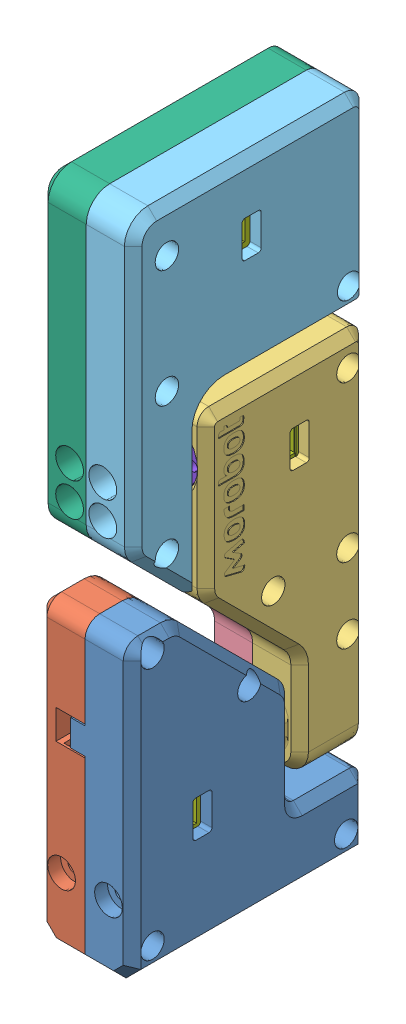
SolidWorks assembly morobot-s-RRR, configuration Standard. Lengths in mm.
Overall size (121.81 228.58 81.15).
12 component instances, 8 part files, 31 mates.
Components (placement in the parent):
- L1_1-4: L1_1 [Standard] at origin size (20.9 101 80)
- L1_2-2: L1_2 [Standard] at origin size (16.29 101 80)
- L2_1-2: L2_1 [Standard] at (-6.6119 1.3517 0) x (0.906308 -0.422618 0) z (0 0 1) size (64.27 117.88 55.7)
- L2_2-2: L2_2 [Standard] at (-6.6119 1.3517 0) x (0.906308 -0.422618 0) z (0 0 1) size (65.64 116.51 55.7)
- L3_1-2: L3_1 [Standard] at (28.5195 4.7304 0) x (0.994056 -0.10887 0) z (0 0 1) size (33.16 120.87 81.15)
- L3_2-2: L3_2 [Standard] at (28.5195 4.7304 0) x (0.994056 -0.10887 0) z (0 0 1) size (28.66 121.22 80.97)
- Motor-2: Motor [Standard] at (0.15 -0.1474 0.15) size (24.42 48.42 41)
- Motor_Drehachse-2: Motor_Drehachse [Standard] at (0.15 -0.1474 0.15) size (23.25 23.25 6.8)
- Motor-3: Motor [Standard] at (0.4 92.6052 -1.15) x (-1 0 0) z (0 0 -1) size (24.42 48.42 41)
- Motor_Drehachse-3: Motor_Drehachse [Standard] at (-5.7288 123.3848 -1.85) x (0.923728 0.383049 0) z (0 0 -1) size (23.25 23.25 6.8)
- Motor-4: Motor [Standard] at (0.25 163.324 -16.1777) size (24.42 48.42 41)
- Motor_Drehachse-4: Motor_Drehachse [Standard] at (-8.1505 165.7066 -16.1777) x (0.851084 -0.525029 0) z (0 0 1) size (23.25 23.25 6.8)
Mates (geometry in assembly coordinates):
- Deckungsgleich15: coincident anti-aligned: plane of L1_1-4 through (13 28.2474 28.15) normal (0 0 -1); plane of Motor-2 through (12.15 27.8526 28.15) normal (0 0 1)
- Deckungsgleich16: coincident anti-aligned: plane of L1_1-4 through (13 -20.1474 28.15) normal (0 0.999848 -0.017452); plane of Motor-2 through (12.15 -20.1474 28.15) normal (0 -0.999848 0.017452)
- Deckungsgleich18: coincident anti-aligned: plane of L1_1-4 through (12.15 0 0) normal (-1 0 0); plane of Motor-2 through (12.15 3.8526 8.15) normal (1 0 0)
- Konzentrisch2: concentric anti-aligned: cylinder of Motor-2 through (0.15 15.8526 -12.85) axis (0 0 1) radius 3.5; cylinder of Motor_Drehachse-2 through (0.15 15.8526 -6.05) axis (0 0 -1) radius 3.6
- Abstand2: distance = 0.7 mm anti-aligned: plane of Motor_Drehachse-2 through (0.15 15.8526 -6.05) normal (0 0 1); plane of Motor-2 through (0.15 15.8526 -5.35) normal (0 0 -1)
- Deckungsgleich20: coincident anti-aligned: plane of L1_1-4 through (0 -17.95 33) normal (-1 0 0); plane of L1_2-2 through (0 0 0) normal (1 0 0)
- Deckungsgleich21: coincident aligned: plane of L1_1-4 through (-16 -31 40) normal (0 -1 0); plane of L1_2-2 through (-16 -31 40) normal (0 -1 0)
- Deckungsgleich22: coincident aligned: plane of L1_1-4 through (0 0 40) normal (0 0 1); plane of L1_2-2 through (0 0 40) normal (0 0 1)
- Deckungsgleich23: coincident anti-aligned: plane of L2_1-2 through (13.15 72.6052 -29.15) normal (0 0 1); plane of Motor-3 through (-11.6 120.6052 -29.15) normal (0 0 -1)
- Deckungsgleich24: coincident anti-aligned: plane of L2_1-2 through (13.15 72.4298 -19.1026) normal (0 0.999848 0.017452); plane of Motor-3 through (-11.6 72.6052 -29.15) normal (0 -0.999848 -0.017452)
- Deckungsgleich25: coincident anti-aligned: plane of L2_1-2 through (12.3 50.7526 -40) normal (-1 0 0); plane of Motor-3 through (12.3 107.6052 -3.5071) normal (1 0 0)
- Konzentrisch3: concentric anti-aligned: cylinder of Motor-3 through (0.4 108.6052 11.85) axis (0 0 -1) radius 3.5; cylinder of Motor_Drehachse-3 through (0.4 108.6052 4.35) axis (0 0 1) radius 3.6
- Deckungsgleich26: coincident anti-aligned: plane of Motor-3 through (0.4 108.6052 4.35) normal (0 0 1); plane of Motor_Drehachse-3 through (0.4 108.6052 4.35) normal (0 0 -1)
- Deckungsgleich27: coincident anti-aligned: plane of L2_1-2 through (0.15 37.7526 -36.6465) normal (-1 0 0); plane of L2_2-2 through (0.15 50.7526 -40) normal (1 0 0)
- Deckungsgleich28: coincident aligned: plane of L2_1-2 through (0.15 50.7526 -40) normal (0 0 -1); plane of L2_2-2 through (0.15 50.7526 -40) normal (0 0 -1)
- Deckungsgleich29: coincident aligned: plane of L2_1-2 through (16.15 125.7526 -17) normal (0 1 0); plane of L2_2-2 through (16.15 125.7526 -17) normal (0 1 0)
- Deckungsgleich30: coincident anti-aligned: plane of L3_2-2 through (-11.75 191.324 11.8223) normal (0 0 -1); plane of Motor-4 through (12.25 191.324 11.8223) normal (0 0 1)
- Deckungsgleich31: coincident anti-aligned: plane of L3_2-2 through (-11.75 191.5038 1.5223) normal (0 -0.999848 -0.017452); plane of Motor-4
- Deckungsgleich33: coincident anti-aligned: plane of L3_2-2 through (-11.75 130.6052 28.5) normal (1 0 0); plane of Motor-4
- Konzentrisch4: concentric anti-aligned: cylinder of Motor-4 through (0.25 179.324 -29.1777) axis (0 0 1) radius 3.5; cylinder of Motor_Drehachse-4 through (0.25 179.324 -22.3777) axis (0 0 -1) radius 3.6
- Abstand3: distance = 0.7 mm anti-aligned: plane of Motor-4 through (0.25 179.324 -21.6777) normal (0 0 -1); plane of Motor_Drehachse-4 through (0.25 179.324 -22.3777) normal (0 0 1)
- Deckungsgleich35: coincident anti-aligned: plane of L3_1-2 through (0.4 92.6052 25.45) normal (-1 0 0); plane of L3_2-2
- Deckungsgleich36: coincident aligned: plane of L3_1-2 through (16.4 195.6052 40) normal (0 0 1); plane of L3_2-2 through (16.4 195.6052 40) normal (0 0 1)
- Deckungsgleich37: coincident aligned: plane of L3_1-2 through (16.4 195.6052 40) normal (0 1 0); plane of L3_2-2
- Konzentrisch5: concentric anti-aligned: circle of L2_1-2; circle of Motor_Drehachse-2
- Abstand4: distance = 2 mm anti-aligned: plane of L1_1-4 through (0 0 -15) normal (0 0 -1); plane of L2_1-2 through (0.15 50.7526 -17) normal (0 0 1)
- Konzentrisch6: concentric anti-aligned: circle of L3_1-2; circle of Motor_Drehachse-3
- Abstand5: distance = 2 mm anti-aligned: plane of L3_1-2 through (16.4 195.6052 17) normal (0 0 -1); plane of L2_1-2 through (108.8484 70.7526 15) normal (0 0 1)
- s_a1: limit planar angle = 1.570796 rad aligned: plane of L2_2-2 through (-15.85 125.7526 -17) normal (-1 0 0); plane of L1_2-2 through (-16 -31 40) normal (0 -1 0); plane of L1_2-2 through (0 0 -40) normal (0 0 -1)
- s_a2: limit planar angle = 1.570796 rad aligned: plane of L3_2-2 through (0.4 195.6052 28.5) normal (0 1 0); plane of L2_2-2 through (-15.85 125.7526 -17) normal (-1 0 0); plane of L1_2-2 through (0 0 -40) normal (0 0 -1)
- s_a3: limit planar angle = 3.694342 rad aligned: plane of Motor_Drehachse-4 through (-8.1505 165.7066 -16.1777) normal (0.851084 -0.525029 0); plane of L3_2-2 through (-15.6 130.6052 28.5) normal (-1 0 0); cylinder of Motor-4 through (-22.2716 175.5915 -29.1777) axis (0 0 1) radius 3.5
